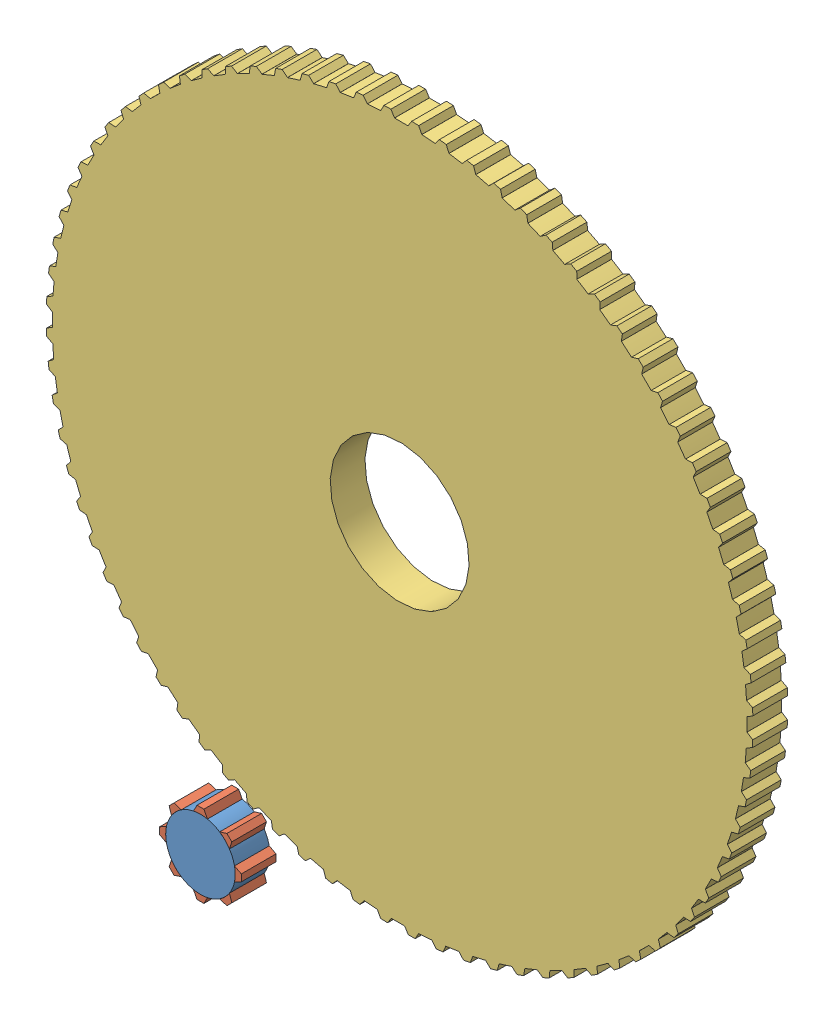
SolidWorks assembly Assem4_1, configuration Default. Lengths in mm.
Overall size (212.15 219.34 20).
10 component instances, 3 part files, 20 mates.
Components (placement in the parent):
- Part2-2: Part2 [Default] at origin size (20 20 10)
- Part3-1: Part3 [Default] at origin size (4.02 1.96 10)
- Part3-2: Part3 [Default] x (0.707107 -0.707107 0) z (0 0 1) size (4.02 1.96 10)
- Part3-3: Part3 [Default] x (0 -1 0) z (0 0 1) size (4.02 1.96 10)
- Part3-4: Part3 [Default] x (-0.707107 -0.707107 0) z (0 0 1) size (4.02 1.96 10)
- Part3-5: Part3 [Default] x (-1 0 0) z (0 0 1) size (4.02 1.96 10)
- Part3-6: Part3 [Default] x (-0.707107 0.707107 0) z (0 0 1) size (4.02 1.96 10)
- Part3-7: Part3 [Default] x (0 1 0) z (0 0 1) size (4.02 1.96 10)
- Part3-8: Part3 [Default] x (0.707107 0.707107 0) z (0 0 1) size (4.02 1.96 10)
- Part1_4-1: Part1_4 [Default] at (47.3332 101.5065 -10) x (0.999033 -0.043972 0) z (0 0 1) size (203.4 203.4 10)
Mates (geometry in assembly coordinates):
- Coincident1: coordinate: point of Part2-2
- Concentric1: concentric aligned: cylinder of Part2-2 through (0 0 10) axis (0 0 -1) radius 10; cylinder of Part3-5 through (0 0 10) axis (0 0 -1) radius 10
- Concentric2: concentric aligned: cylinder of Part2-2 through (0 0 10) axis (0 0 -1) radius 10; cylinder of Part3-8 through (0 0 10) axis (0 0 -1) radius 10
- Concentric3: concentric aligned: cylinder of Part2-2 through (0 0 10) axis (0 0 -1) radius 10; cylinder of Part3-4 through (0 0 10) axis (0 0 -1) radius 10
- Concentric4: concentric aligned: cylinder of Part2-2 through (0 0 10) axis (0 0 -1) radius 10; cylinder of Part3-2 through (0 0 10) axis (0 0 -1) radius 10
- Concentric5: concentric aligned: cylinder of Part2-2 through (0 0 10) axis (0 0 -1) radius 10; cylinder of Part3-3 through (0 0 10) axis (0 0 -1) radius 10
- Concentric6: concentric aligned: cylinder of Part2-2 through (0 0 10) axis (0 0 -1) radius 10; cylinder of Part3-7 through (0 0 10) axis (0 0 -1) radius 10
- Concentric7: concentric aligned: cylinder of Part2-2 through (0 0 10) axis (0 0 -1) radius 10; cylinder of Part3-1 through (0 0 10) axis (0 0 -1) radius 10
- Concentric8: concentric aligned: cylinder of Part2-2 through (0 0 10) axis (0 0 -1) radius 10; cylinder of Part3-6 through (0 0 10) axis (0 0 -1) radius 10
- Coincident3: coincident aligned: plane of Part2-2 through (0 0 10) normal (0 0 1); plane of Part3-8 through (0 0 10) normal (0 0 1)
- Coincident4: coincident aligned: plane of Part2-2 through (0 0 10) normal (0 0 1); plane of Part3-1 through (0 0 10) normal (0 0 1)
- Coincident5: coincident aligned: plane of Part2-2 through (0 0 10) normal (0 0 1); plane of Part3-2 through (0 0 10) normal (0 0 1)
- Coincident6: coincident aligned: plane of Part2-2 through (0 0 10) normal (0 0 1); plane of Part3-3 through (0 0 10) normal (0 0 1)
- Coincident7: coincident aligned: plane of Part2-2 through (0 0 10) normal (0 0 1); plane of Part3-4 through (0 0 10) normal (0 0 1)
- Coincident8: coincident aligned: plane of Part2-2 through (0 0 10) normal (0 0 1); plane of Part3-5 through (0 0 10) normal (0 0 1)
- Coincident9: coincident aligned: plane of Part2-2 through (0 0 10) normal (0 0 1); plane of Part3-7 through (0 0 10) normal (0 0 1)
- Coincident10: coincident aligned: plane of Part2-2 through (0 0 10) normal (0 0 1); plane of Part3-6 through (0 0 10) normal (0 0 1)
- Coincident15: coincident anti-aligned: plane of Part1_4-1 through (47.3332 101.5065 0) normal (0 0 -1)
- Concentric9: concentric aligned: circle of Part1_4-1
- Coincident17: coincident anti-aligned: plane of Part1_4-1 through (47.3332 101.5065 0) normal (0 0 -1)
